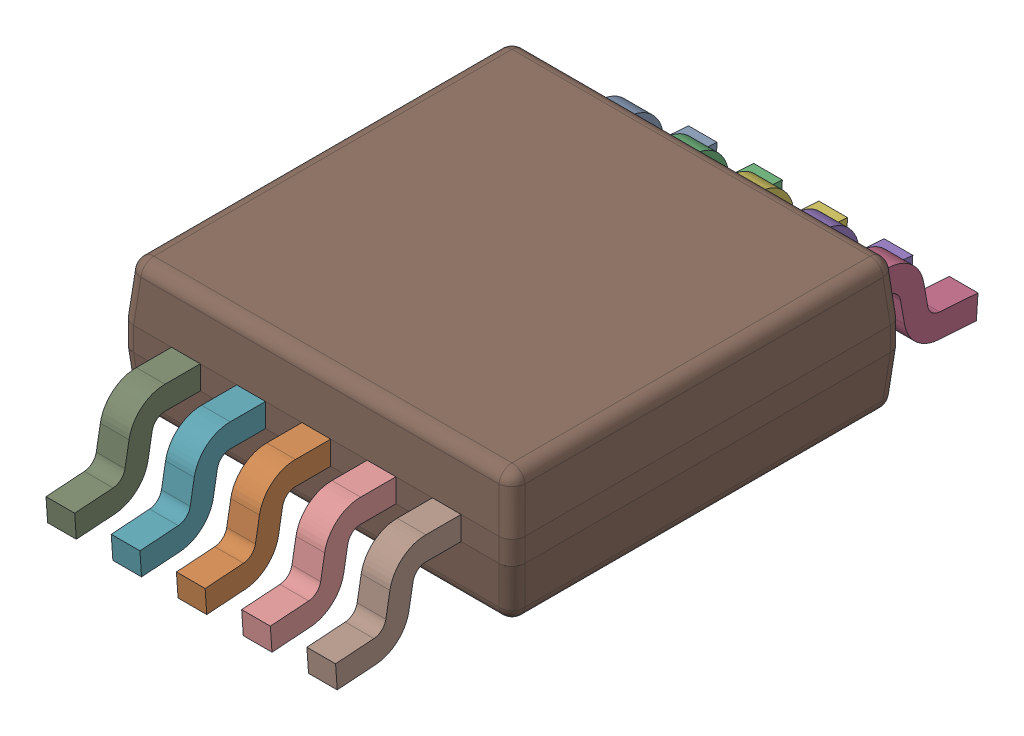
SolidWorks assembly 6132016496, configuration 默认. Lengths in mm.
Overall size (3 1.1 4.93).
11 component instances, 2 part files, 0 mates.
Components (placement in the parent):
- LEAD-SO-1: LEAD-SO [默认] at (-1 -0.44 -1.9) x (-1 0 0) z (0 0 -1) size (0.22 0.69 0.96)
- LEAD-SO-2: LEAD-SO [默认] at (0 -0.44 1.9) size (0.22 0.69 0.96)
- LEAD-SO-3: LEAD-SO [默认] at (-0.5 -0.44 -1.9) x (-1 0 0) z (0 0 -1) size (0.22 0.69 0.96)
- LEAD-SO-4: LEAD-SO [默认] at (1 -0.44 -1.9) x (-1 0 0) z (0 0 -1) size (0.22 0.69 0.96)
- LEAD-SO-5: LEAD-SO [默认] at (0.5 -0.44 -1.9) x (-1 0 0) z (0 0 -1) size (0.22 0.69 0.96)
- LEAD-SO-6: LEAD-SO [默认] at (0 -0.44 -1.9) x (-1 0 0) z (0 0 -1) size (0.22 0.69 0.96)
- LEAD-SO-7: LEAD-SO [默认] at (-0.5 -0.44 1.9) size (0.22 0.69 0.96)
- LEAD-SO-8: LEAD-SO [默认] at (1 -0.44 1.9) size (0.22 0.69 0.96)
- LEAD-SO-9: LEAD-SO [默认] at (-1 -0.44 1.9) size (0.22 0.69 0.96)
- LEAD-SO-10: LEAD-SO [默认] at (0.5 -0.44 1.9) size (0.22 0.69 0.96)
- BODY-SO-1: BODY-SO [默认] at origin size (3 1 3)
